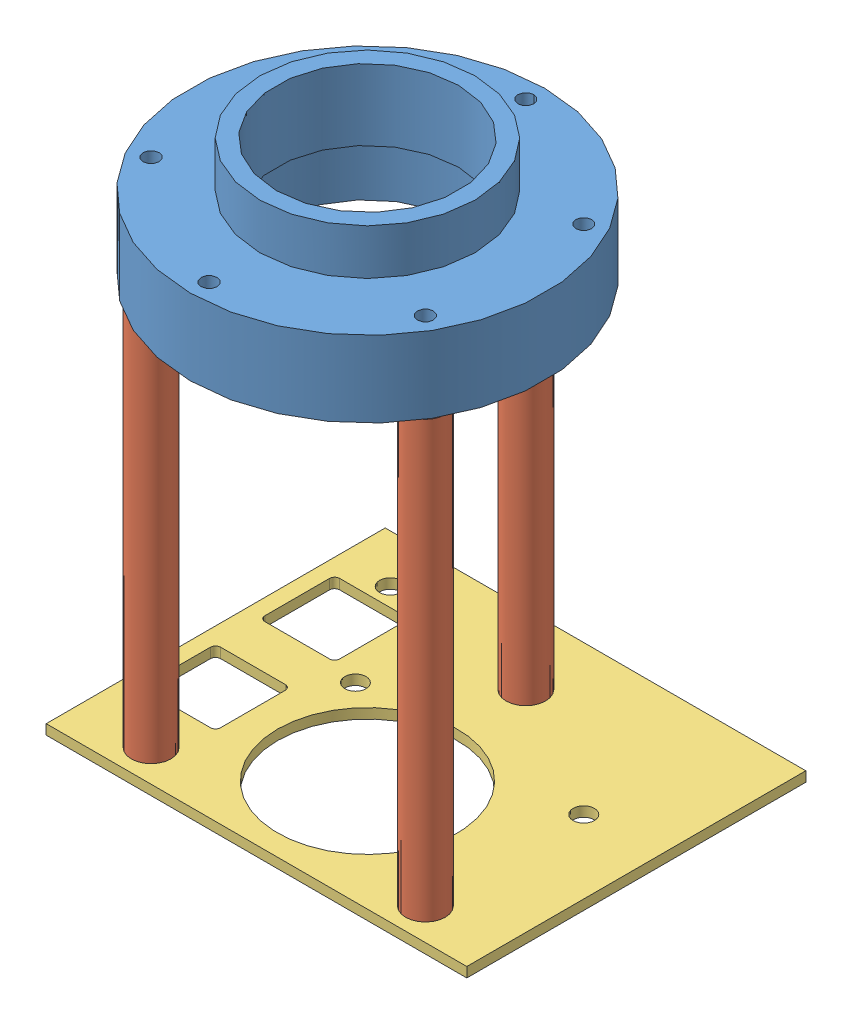
SolidWorks assembly assembly, configuration Default. Lengths in mm.
Overall size (42.16 56.83 40.64).
5 component instances, 3 part files, 8 mates.
Components (placement in the parent):
- Adapter_2-1: Adapter_2 [Default] at origin size (35.56 12.19 35.56)
- Standoffs_1718-1: Standoffs_1718 [Default] at (-13.7482 -43.6372 7.9375) size (3.97 46.69 3.97)
- Standoffs_1718-2: Standoffs_1718 [Default] at (13.7482 -43.6372 7.9375) size (3.97 46.69 3.97)
- Standoffs_1718-3: Standoffs_1718 [Default] at (0 -43.6372 -15.875) size (3.97 46.69 3.97)
- Stabilizer-1: Stabilizer [Default] at (105.8664 -44.6546 141.169) x (1 0 0) z (0 -1 0) size (42.16 33.99 1)
Mates (geometry in assembly coordinates):
- Coincident1: coincident anti-aligned: plane of Adapter_2-1 through (0 0 0) normal (0 -1 0); plane of Standoffs_1718-1 through (-13.7482 0 7.9375) normal (0 1 0)
- Concentric1: concentric anti-aligned: circle of Adapter_2-1; circle of Standoffs_1718-1
- Coincident2: coincident anti-aligned: plane of Adapter_2-1 through (0 0 0) normal (0 -1 0); plane of Standoffs_1718-2 through (13.7482 0 7.9375) normal (0 1 0)
- Concentric2: concentric anti-aligned: circle of Adapter_2-1; circle of Standoffs_1718-2
- Coincident3: coincident anti-aligned: plane of Adapter_2-1 through (0 0 0) normal (0 -1 0); plane of Standoffs_1718-3 through (0 0 -15.875) normal (0 1 0)
- Concentric3: concentric anti-aligned: circle of Adapter_2-1; circle of Standoffs_1718-3
- Concentric4: concentric anti-aligned: circle of Standoffs_1718-1; circle of Stabilizer-1
- Concentric5: concentric anti-aligned: circle of Standoffs_1718-2; circle of Stabilizer-1
